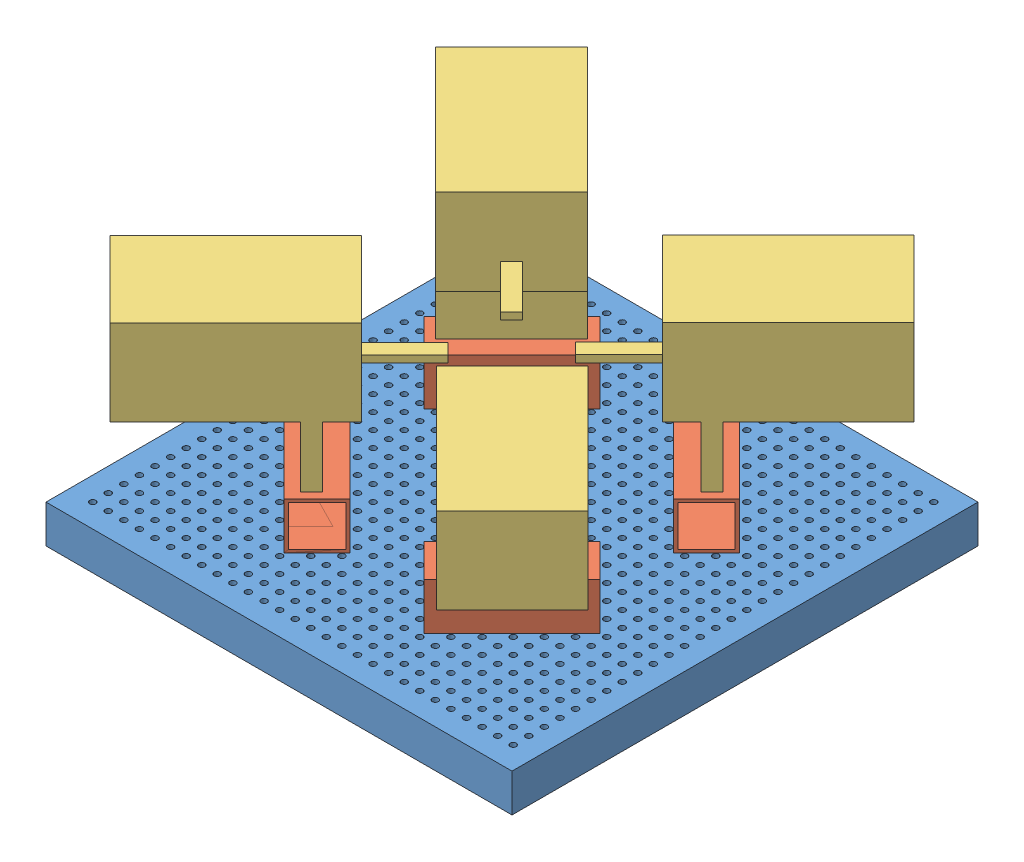
SolidWorks assembly BiAxialAssembly, configuration Default. Lengths in mm.
Overall size (779.71 377 779.71).
10 component instances, 3 part files, 8 mates.
Components (placement in the parent):
- Breadboard_UnknownHeight-1: Breadboard_UnknownHeight [Default] at (456.6667 247.0088 -632.6004) size (760 62 760)
- MetalBaseTubeThing-2: MetalBaseTubeThing [Default] at (543.4295 347.1088 -863.0473) x (0.707107 0 -0.707107) z (0.707107 0 0.707107) size (76.2 76.2 203.2)
- MetalBaseTubeThing-3: MetalBaseTubeThing [Default] at (225.9812 347.1088 -719.3632) x (-0.707107 0 -0.707107) z (0.707107 0 -0.707107) size (76.2 76.2 203.2)
- MetalBaseTubeThing-4: MetalBaseTubeThing [Default] at (687.1136 347.1088 -545.5989) x (0.707107 0 0.707107) z (-0.707107 0 0.707107) size (76.2 76.2 203.2)
- BiAxialTest-10: BiAxialTest [Default] at (682.0013 484.0088 -407.4798) x (-0.707107 0 -0.707107) z (0.707107 0 -0.707107) size (390 238.8 175)
- BiAxialTest-11: BiAxialTest [Default] at (681.5487 484.0088 -857.9349) x (-0.707107 0 0.707107) z (-0.707107 0 -0.707107) size (390 238.8 175)
- BiAxialTest-12: BiAxialTest [Default] at (231.0935 484.0088 -857.4824) x (0.707107 0 0.707107) z (-0.707107 0 0.707107) size (390 238.8 175)
- BiAxialTest-13: BiAxialTest [Default] at (231.5461 484.0088 -407.0272) x (0.707107 0 -0.707107) z (0.707107 0 0.707107) size (390 238.8 175)
- MetalBaseTubeThing-5: MetalBaseTubeThing [Default] at (369.6653 347.1088 -401.9148) x (-0.707107 0 0.707107) z (-0.707107 0 -0.707107) size (76.2 76.2 203.2)
- MetalBaseTubeThing-6: MetalBaseTubeThing [Default] at (369.6653 347.1088 -401.9148) x (-0.707107 0 0.707107) z (-0.707107 0 -0.707107) size (76.2 76.2 203.2)
Mates (geometry in assembly coordinates):
- Coincident7: coincident anti-aligned: plane of Breadboard_UnknownHeight-1 through (456.6667 309.0088 -632.6004) normal (0 1 0); plane of MetalBaseTubeThing-2 through (660.1729 309.0088 -692.4224) normal (0 -1 0)
- Parallel9: parallel anti-aligned: plane of Breadboard_UnknownHeight-1 through (76.6667 247.0088 -252.6004) normal (0.707107 0 -0.707107); plane of MetalBaseTubeThing-2 through (660.1729 309.0088 -692.4224) normal (-0.707107 0 0.707107)
- Coincident9: coincident: point of Breadboard_UnknownHeight-1; moEndPointRef_w of MetalBaseTubeThing-2
- Distance4: distance = 275 mm: unknown of MetalBaseTubeThing-2; unknown of Breadboard_UnknownHeight-1
- Coincident17: coincident anti-aligned: plane of MetalBaseTubeThing-4 through (516.4888 385.2088 -428.8556) normal (0 1 0); plane of BiAxialTest_UnknownWidth-10 through (682.0013 385.2088 -407.4798) normal (0 -1 0)
- Perpendicular1: perpendicular: line of Breadboard_UnknownHeight-1 through (76.6667 309.0088 -1012.6004) axis (0.707107 0 0.707107); line of BiAxialTest_UnknownWidth-10 through (690.8401 385.2088 -522.3846) axis (-0.707107 0 0.707107)
- Distance9: distance = 13.78 mm: line of BiAxialTest_UnknownWidth-10 through (690.8401 385.2088 -522.3846) axis (-0.707107 0 -0.707107); line of MetalBaseTubeThing-4 through (714.0544 385.2088 -518.6582) axis (-0.707107 0 -0.707107)
- Distance10: distance = 19.05 mm: line of BiAxialTest_UnknownWidth-10 through (690.8401 385.2088 -522.3846) axis (-0.707107 0 0.707107); line of MetalBaseTubeThing-4 through (570.3703 385.2088 -374.9741) axis (0.707107 0 -0.707107)
